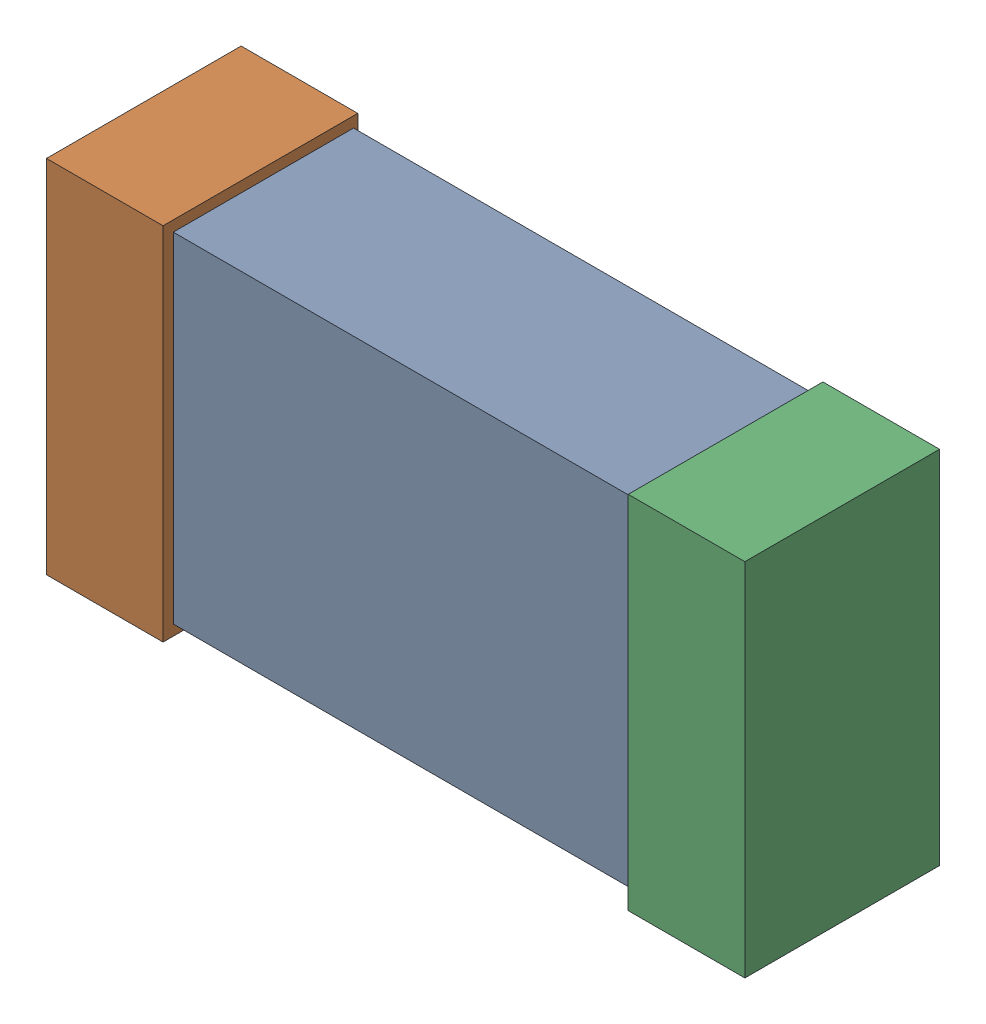
SolidWorks assembly C17, configuration Default. Lengths in mm.
Overall size (1.65 0.85 0.46).
6 component instances, 2 part files, 0 mates.
Components (placement in the parent):
- 432120720_10-1: 432120720_10 [Default] at (15.0566 22.0499 -0.8615) size (1.5 0.8 0.42)
  - Extruded (12)-1: Extruded (12) [Default] at origin size (1.5 0.8 0.42)
- 432120464_20-1: 432120464_20 [Default] at (14.3708 22.0499 -0.8715) size (0.28 0.85 0.46)
  - Extruded (11)-1: Extruded (11) [Default] at origin size (0.28 0.85 0.46)
- 432120464_21-1: 432120464_21 [Default] at (15.7423 22.0499 -0.8715) size (0.28 0.85 0.46)
  - Extruded (11)-1: Extruded (11) [Default] at origin size (0.28 0.85 0.46)
